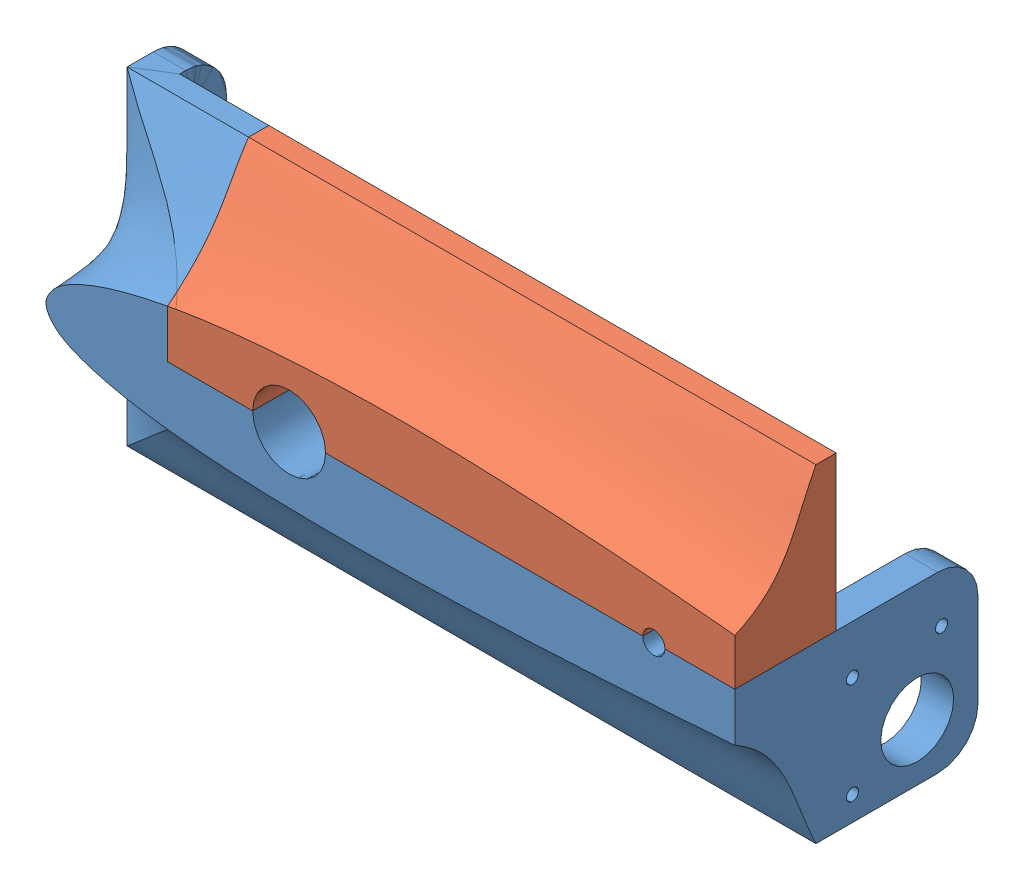
SolidWorks assembly clampAssem_v1c, configuration Default. Lengths in mm.
Overall size (271.04 220 483.15).
2 component instances, 2 part files, 3 mates.
Components (placement in the parent):
- clampBottom_v1.1-1: clampBottom_v1.1 [Default] at (-78.2186 157.5924 266.0088) size (271.04 220 483.15)
- clampTop_v1.1-2: clampTop_v1.1 [Default] at (-78.2186 157.5924 266.0088) size (271 81.01 25.01)
Mates (geometry in assembly coordinates):
- Coincident6: coincident aligned: plane of clampBottom_v1.1-1 through (91.7814 232.6907 266.019) normal (1 0 0); plane of clampTop_v1.1-2 through (91.7814 232.6907 266.019) normal (1 0 0)
- Coincident7: coincident anti-aligned: plane of clampBottom_v1.1-1 through (91.7814 160.0924 266.0156) normal (0 1 0); plane of clampTop_v1.1-2 through (91.7814 160.0924 266.0156) normal (0 -1 0)
- Coincident8: coincident aligned: plane of clampBottom_v1.1-1 through (-78.1405 158.3399 266.0088) normal (0 0 1); plane of clampTop_v1.1-2 through (-78.1405 158.3399 266.0088) normal (0 0 1)
